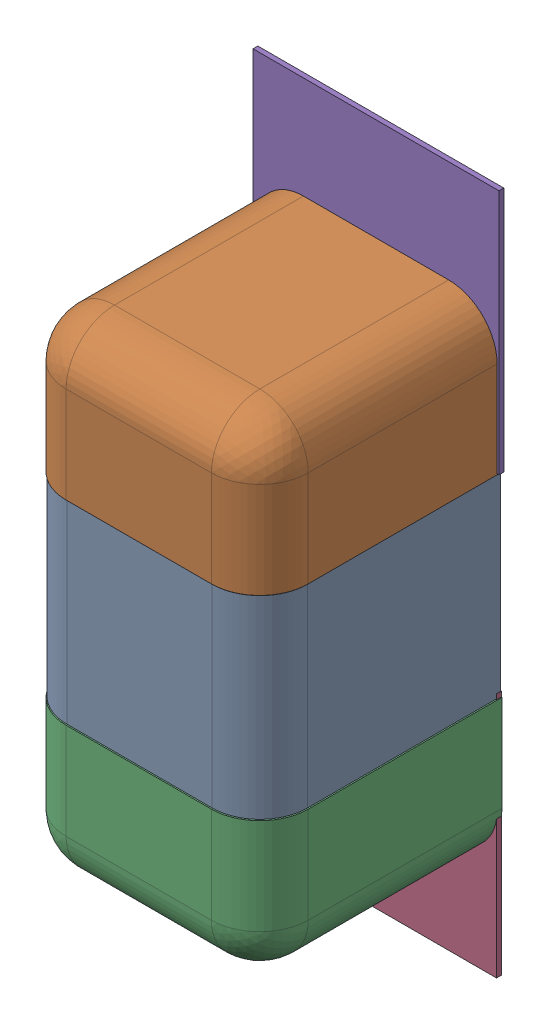
SolidWorks assembly C47, configuration Défaut. Lengths in mm.
Overall size (0.51 1.41 0.5).
8 component instances, 4 part files, 0 mates.
Components (placement in the parent):
- 6501210464-1: 6501210464 [Défaut] at (56.8452 -15.7988 0) x (0 -1 0) z (-1 0 0) size (1 0.5 0.5)
  - Open CASCADE STEP translator 7.5 2.33.1.1-1: Open CASCADE STEP translator 7.5 2.33.1.1 [Défaut] at origin size (0.4 0.5 0.5)
  - Open CASCADE STEP translator 7.5 2.33.1.2-1: Open CASCADE STEP translator 7.5 2.33.1.2 [Défaut] at origin size (0.3 0.5 0.5)
  - Open CASCADE STEP translator 7.5 2.33.1.3-1: Open CASCADE STEP translator 7.5 2.33.1.3 [Défaut] at origin size (0.3 0.5 0.5)
- 6504207776-1: 6504207776 [Défaut] at (56.84 -16.2438 0) size (0.51 0.51 0.01)
  - Extruded-1: Extruded [Défaut] at origin size (0.51 0.51 0.01)
- 6504207776-2: 6504207776 [Défaut] at (56.8452 -15.3415 0) size (0.51 0.51 0.01)
  - Extruded-1: Extruded [Défaut] at origin size (0.51 0.51 0.01)
